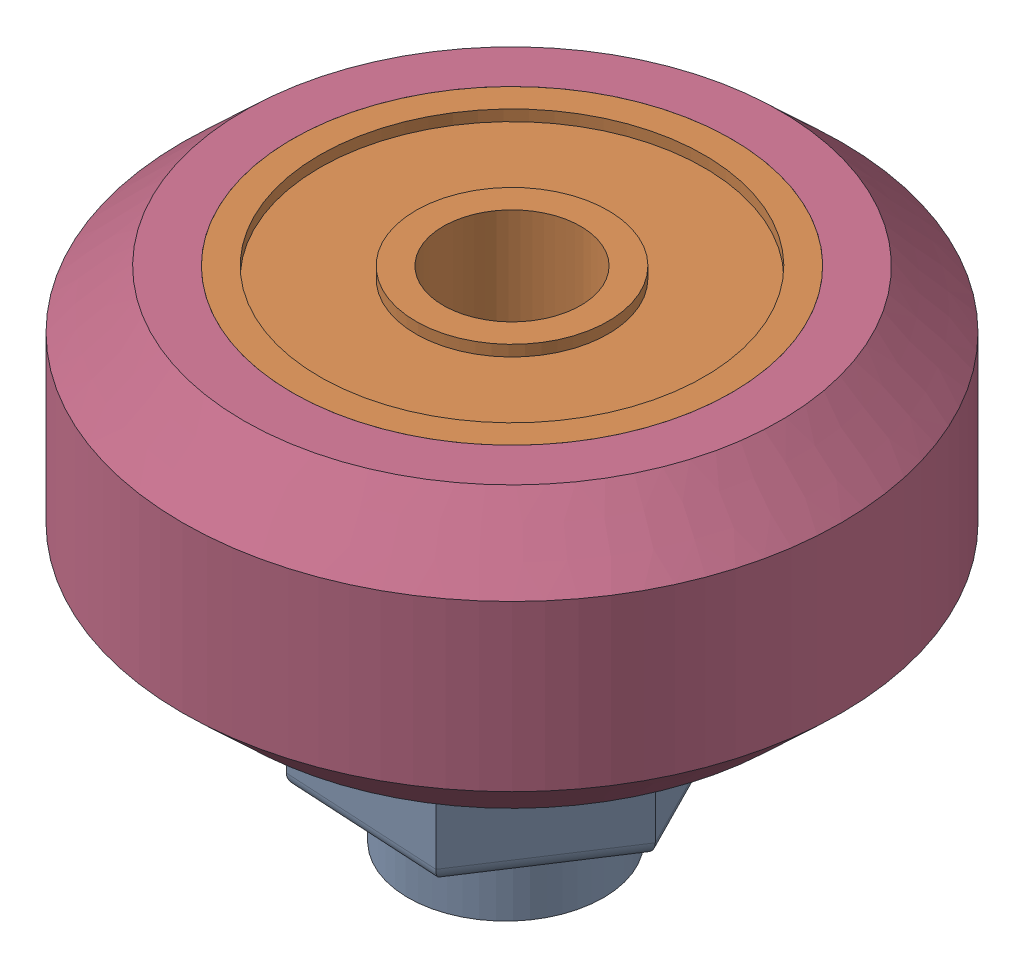
SolidWorks assembly V Wheel, configuration Default. Lengths in mm.
Overall size (24 18.7 24).
4 component instances, 3 part files, 6 mates.
Components (placement in the parent):
- Ecentric Spacer(6mm) 8.5mm overall height-1: Ecentric Spacer(6mm) 8.5mm overall height [Default] at (0 8.5 0) x (0.837169 0 0.546944) z (0.546944 0 -0.837169) size (10 8.5 11.55)
- 625 ZZ-1: 625 ZZ [Default] at (0.6614 16.2 0.4321) x (0.999811 0 -0.019452) z (0.019452 0 0.999811) size (16 5 16)
- 625 ZZ-2: 625 ZZ [Default] at (0.6614 11 0.4321) size (16 5 16)
- V Wheel Rubber-1: V Wheel Rubber [Default] at (0.6614 13.6 0.4321) x (0 1 0) z (0 0 1) size (10.2 24 24)
Mates (geometry in assembly coordinates):
- Concentric21: concentric aligned: cylinder of 625 ZZ-1 through (0.2703 8.5 0.1666) axis (0 1 0) radius 2.5; cylinder of 625 ZZ-2 through (0 8.5 0) axis (0 1 0) radius 2.5
- Concentric31: concentric anti-aligned: cylinder of 625 ZZ-2 through (0 8.5 0) axis (0 1 0) radius 2.5; cylinder of V Wheel Rubber-1 through (0 10.1665 0) axis (0 -1 0) radius 8
- Coincident1: coincident aligned: plane of 625 ZZ-1 through (0.2703 13.5 0.1666) normal (0 1 0); plane of V Wheel Rubber-1 through (-9.77 18.7 0) normal (0 1 0)
- Coincident2: coincident aligned: plane of 625 ZZ-2 through (0 8.5 0) normal (0 -1 0); plane of V Wheel Rubber-1 through (-9.77 8.5 0) normal (0 -1 0)
- Coincident4: coincident anti-aligned: plane of Ecentric Spacer(6mm) 8.5mm overall height-1 through (0 8.5 0) normal (0 1 0); plane of 625 ZZ-2 through (0 8.5 0) normal (0 -1 0)
- Concentric32: concentric anti-aligned: cylinder of Ecentric Spacer(6mm) 8.5mm overall height-1 through (0.6614 8.5 0.4321) axis (0 -1 0) radius 2.5; cylinder of 625 ZZ-1 through (0.6614 13.7 0.4321) axis (0 1 0) radius 2.5
